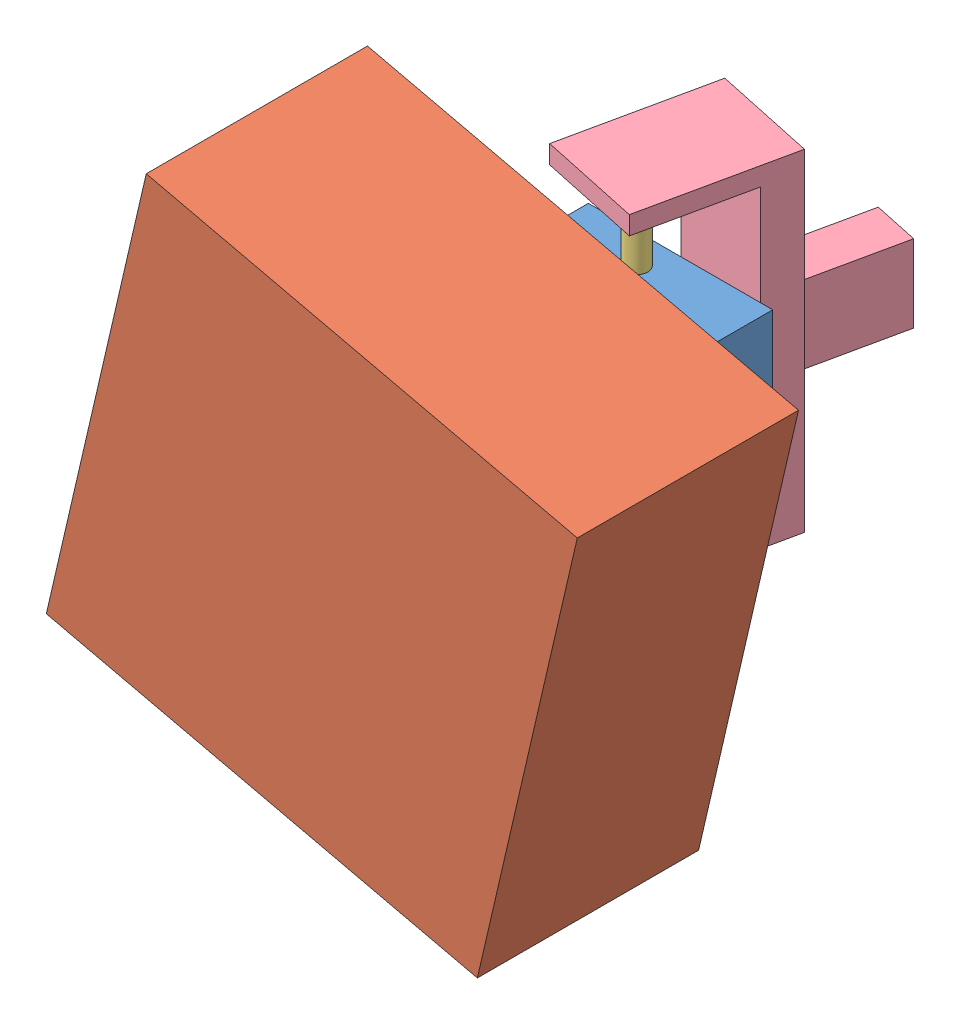
SolidWorks assembly clawpeghone, configuration Default. Lengths in mm.
Overall size (144 144 157.23).
5 component instances, 4 part files, 9 mates.
Components (placement in the parent):
- cube peg-1: cube peg [默认] at (50.2985 54.7658 13.8064) size (50 50 90)
- cubehole-1: cubehole [默认] at (38.0685 65.2627 53.8064) x (0.974166 -0.225834 0) z (0 0 1) size (120 120 60)
- cylindersensor-1: cylindersensor [Default] at (44.5871 27.1038 19.5286) x (1 0 0) z (0 -1 0) size (6 6 15)
- cylindersensor-2: cylindersensor [Default] at (44.5871 77.1038 24.2433) x (1 0 0) z (0 1 0) size (6 6 15)
- claw-1: claw [Default] at (37.3323 49.4291 -2.0977) x (0 1 0) z (0.209586 0 -0.97779) size (90 28.12 70)
Mates (geometry in assembly coordinates):
- 重合1: coincident anti-aligned: plane of cube peg-1 through (50.2985 54.7658 103.8064) normal (0 0 1); plane of cubehole-1 through (38.0685 65.2627 103.8064) normal (0 0 -1)
- 重合2: coincident: line of cube peg-1 through (69.9744 77.1038 103.8064) axis (0 0 -1); plane of cubehole-1 through (22.5245 88.1038 103.8064) normal (-0.225834 -0.974166 0)
- 重合3: coincident: line of cube peg-1 through (69.9744 27.1038 103.8064) axis (0 0 -1); plane of cubehole-1 through (80.9744 74.5537 103.8064) normal (-0.974166 0.225834 0)
- 重合5: coincident: line of cube peg-1 through (19.9744 27.1038 103.8064) axis (0 0 -1); plane of cubehole-1 through (8.9744 29.6538 103.8064) normal (0.225834 0.974166 0)
- 重合6: coincident anti-aligned: plane of cube peg-1 through (19.9744 27.1038 103.8064) normal (0 -1 0); plane of cylindersensor-1 through (41.1765 27.1038 21.8859) normal (0 1 0)
- 重合7: coincident anti-aligned: plane of cube peg-1 through (19.9744 77.1038 103.8064) normal (0 1 0); plane of cylindersensor-2 through (41.1765 77.1038 21.8859) normal (0 -1 0)
- 重合8: coincident anti-aligned: plane of cylindersensor-1 through (41.1765 12.1038 21.8859) normal (0 -1 0); plane of claw-1 through (31.0447 12.1038 27.2361) normal (0 1 0)
- 重合9: coincident anti-aligned: plane of cylindersensor-2 through (41.1765 92.1038 21.8859) normal (0 1 0); plane of claw-1 through (31.0447 92.1038 27.2361) normal (0 -1 0)
- 同心1: concentric anti-aligned: cylinder of cylindersensor-1 through (41.1765 12.1038 21.8859) axis (0 1 0) radius 3; cylinder of cylindersensor-2 through (41.1765 92.1038 21.8859) axis (0 -1 0) radius 3
